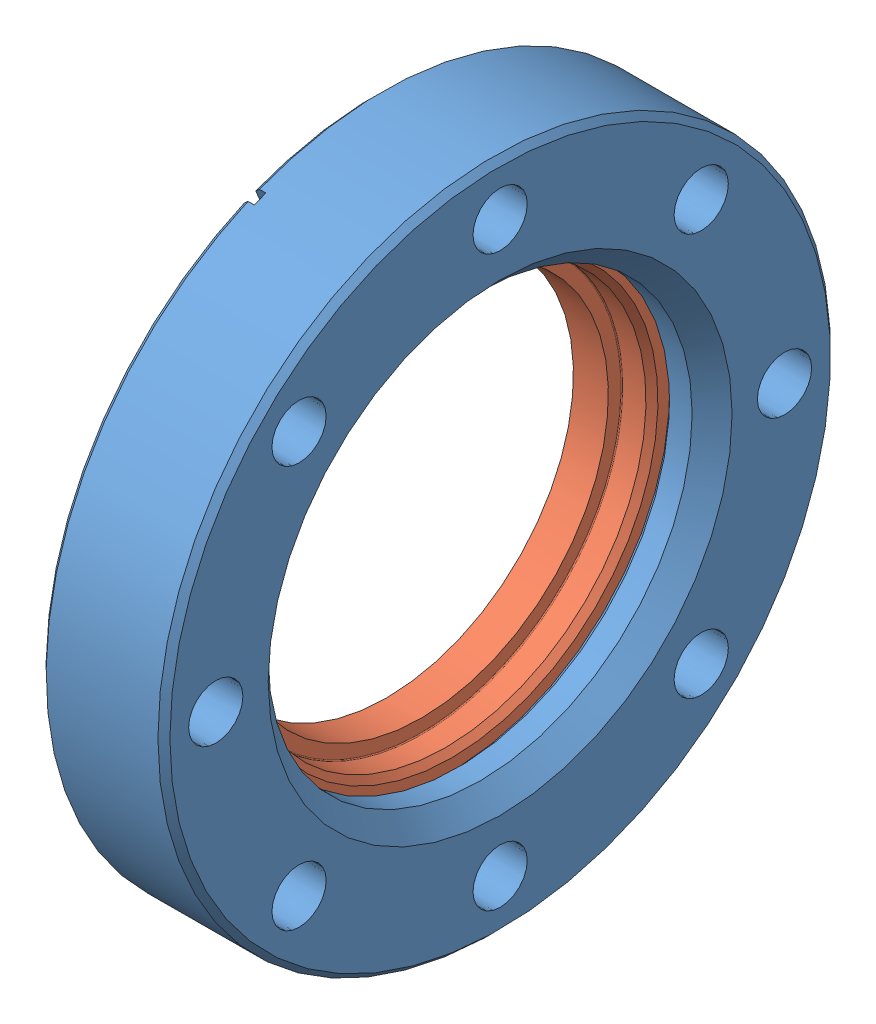
SolidWorks assembly 120017, configuration Default. Lengths in mm.
Overall size (15.76 85.6 85.6).
2 component instances, 2 part files, 2 mates.
Components (placement in the parent):
- 920003-1: 920003 [Default] at (31.0867 47.2204 60.2741) size (15.76 85.6 85.6)
- 910017-1: 910017 [Default] at (31.7471 47.2204 60.2741) x (1 0 0) z (0 0.031066 0.999517) size (8.89 61.67 61.67)
Mates (geometry in assembly coordinates):
- Concentric1: concentric: cylinder of 920003-1 through (31.0867 47.2204 60.2741) axis (-1 0 0) radius 42.799; cylinder of 910017-1 through (31.7471 47.2204 60.2741) axis (-1 0 0) radius 30.8356
- Coincident1: coincident anti-aligned: plane of 920003-1 through (40.6371 78.1703 60.2741) normal (-1 0 0); plane of 910017-1 through (40.6371 78.0412 59.3161) normal (1 0 0)
